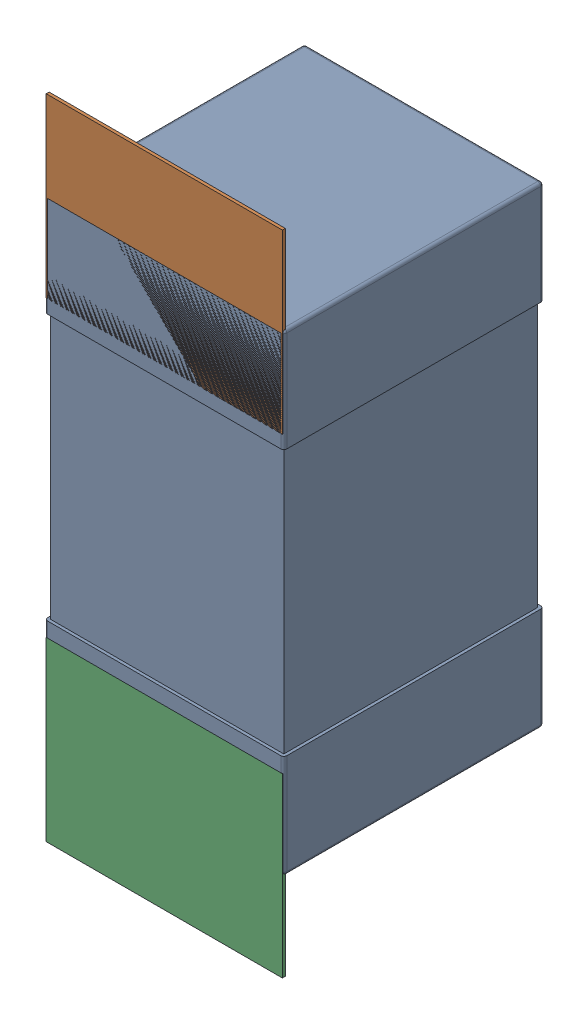
SolidWorks assembly C110, configuration Défaut. Lengths in mm.
Overall size (0.81 2.19 0.88).
5 component instances, 2 part files, 0 mates.
Components (placement in the parent):
- 0603_C-1: 0603_C [Défaut] at (6.3043 -8.5544 -2.0818) x (0 -1 0) z (0 0 -1) size (1.6 0.81 0.88)
- 8260087904-1: 8260087904 [Défaut] at (6.3043 -8.2095 -2.0918) size (0.8 0.6 0.01)
  - Extruded_1211-1: Extruded_1211 [Défaut] at origin size (0.8 0.6 0.01)
- 8260087904-2: 8260087904 [Défaut] at (6.3043 -9.8044 -2.0918) size (0.8 0.6 0.01)
  - Extruded_1211-1: Extruded_1211 [Défaut] at origin size (0.8 0.6 0.01)
